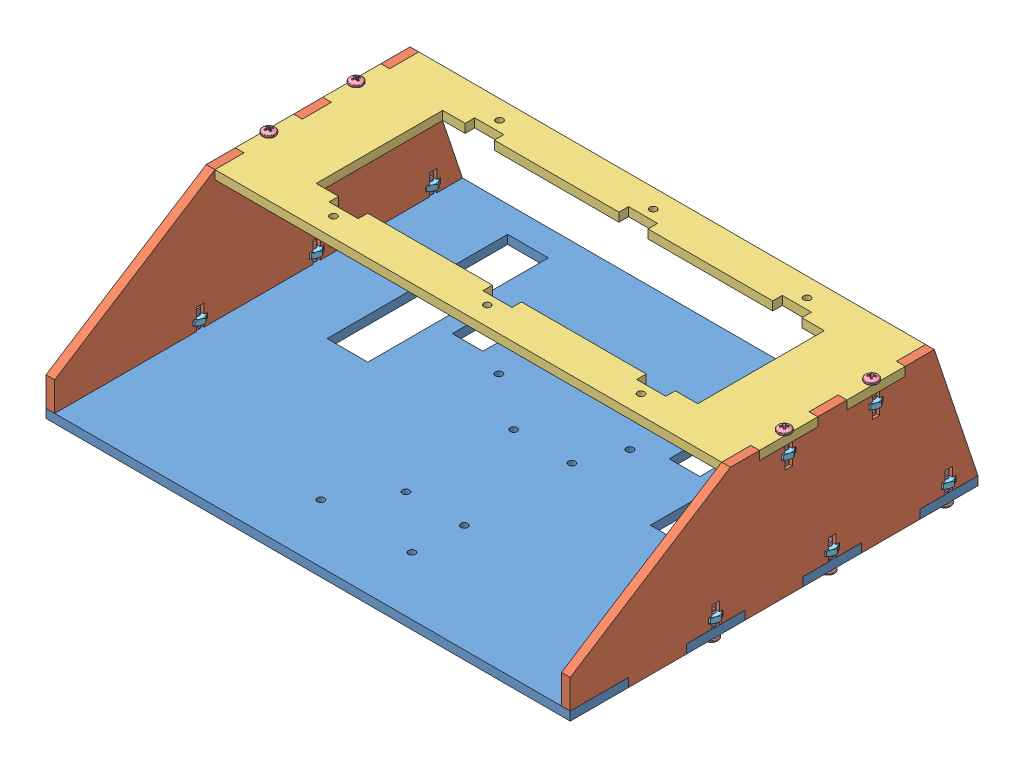
SolidWorks assembly Frame Assembly, configuration Default. Lengths in mm.
Overall size (233.62 64.89 177.8).
24 component instances, 5 part files, 52 mates.
Components (placement in the parent):
- Base Plate-1: Base Plate [Default] at (0 0 -88.9) x (-1 0 0) z (0 0 -1) size (228.6 3.81 177.8)
- Side Plate-1: Side Plate [Default] at (-114.3 0 -88.9) size (3.81 60.96 177.8)
- Side Plate-2: Side Plate [Default] at (110.49 0 -88.9) size (3.81 60.96 177.8)
- Top Plate-1: Top Plate [Default] at (0 57.15 -114.3) x (-1 0 0) z (0 0 -1) size (228.6 3.81 88.9)
- 91772A110_18-8 SS PAN HEAD PHILLIPS MACHINE SCREW-1: 91772A110_18-8 SS PAN HEAD PHILLIPS MACHINE SCREW [91772A110] at (112.395 12.7 -63.5) x (0.947469 0 0.319849) z (0 -1 0) size (5.56 5.56 14.77)
- 91772A110_18-8 SS PAN HEAD PHILLIPS MACHINE SCREW-2: 91772A110_18-8 SS PAN HEAD PHILLIPS MACHINE SCREW [91772A110] at (112.395 48.26 -133.35) x (-0.618252 0 -0.78598) z (0 1 0) size (5.56 5.56 14.77)
- 91772A110_18-8 SS PAN HEAD PHILLIPS MACHINE SCREW-3: 91772A110_18-8 SS PAN HEAD PHILLIPS MACHINE SCREW [91772A110] at (112.395 48.26 -95.25) x (-0.748146 0 -0.663534) z (0 1 0) size (5.56 5.56 14.77)
- 91772A110_18-8 SS PAN HEAD PHILLIPS MACHINE SCREW-4: 91772A110_18-8 SS PAN HEAD PHILLIPS MACHINE SCREW [91772A110] at (112.395 12.7 -114.3) x (0.947469 0 0.319849) z (0 -1 0) size (5.56 5.56 14.77)
- 91772A110_18-8 SS PAN HEAD PHILLIPS MACHINE SCREW-5: 91772A110_18-8 SS PAN HEAD PHILLIPS MACHINE SCREW [91772A110] at (112.395 12.7 -165.1) x (0.947469 0 0.319849) z (0 -1 0) size (5.56 5.56 14.77)
- 91772A110_18-8 SS PAN HEAD PHILLIPS MACHINE SCREW-11: 91772A110_18-8 SS PAN HEAD PHILLIPS MACHINE SCREW [91772A110] at (-112.395 12.7 -165.1) x (0.947469 0 0.319849) z (0 -1 0) size (5.56 5.56 14.77)
- 91772A110_18-8 SS PAN HEAD PHILLIPS MACHINE SCREW-12: 91772A110_18-8 SS PAN HEAD PHILLIPS MACHINE SCREW [91772A110] at (-112.395 48.26 -133.35) x (0.947469 0 0.319849) z (0 1 0) size (5.56 5.56 14.77)
- 91772A110_18-8 SS PAN HEAD PHILLIPS MACHINE SCREW-13: 91772A110_18-8 SS PAN HEAD PHILLIPS MACHINE SCREW [91772A110] at (-112.395 12.7 -63.5) x (0.947469 0 0.319849) z (0 -1 0) size (5.56 5.56 14.77)
- 91772A110_18-8 SS PAN HEAD PHILLIPS MACHINE SCREW-14: 91772A110_18-8 SS PAN HEAD PHILLIPS MACHINE SCREW [91772A110] at (-112.395 12.7 -114.3) x (0.947469 0 0.319849) z (0 -1 0) size (5.56 5.56 14.77)
- 91772A110_18-8 SS PAN HEAD PHILLIPS MACHINE SCREW-15: 91772A110_18-8 SS PAN HEAD PHILLIPS MACHINE SCREW [91772A110] at (-112.395 48.26 -95.25) x (0.947469 0 0.319849) z (0 1 0) size (5.56 5.56 14.77)
- 90480A005_LOW-STRENGTH STEEL HEX NUT-1: 90480A005_LOW-STRENGTH STEEL HEX NUT [90480A005] at (-112.395 7.5406 -165.1) x (-0.899638 0 -0.436636) z (0.436636 0 -0.899638) size (6.35 2.87 7.33)
- 90480A005_LOW-STRENGTH STEEL HEX NUT-2: 90480A005_LOW-STRENGTH STEEL HEX NUT [90480A005] at (-112.395 7.5406 -114.3) x (0.945332 0 0.326111) z (-0.326111 0 0.945332) size (6.35 2.87 7.33)
- 90480A005_LOW-STRENGTH STEEL HEX NUT-3: 90480A005_LOW-STRENGTH STEEL HEX NUT [90480A005] at (-112.395 53.4194 -95.25) x (0.945332 0 0.326111) z (-0.326111 0 0.945332) size (6.35 2.87 7.33)
- 90480A005_LOW-STRENGTH STEEL HEX NUT-4: 90480A005_LOW-STRENGTH STEEL HEX NUT [90480A005] at (112.395 7.5406 -114.3) x (0.917174 0 0.398486) z (-0.398486 0 0.917174) size (6.35 2.87 7.33)
- 90480A005_LOW-STRENGTH STEEL HEX NUT-5: 90480A005_LOW-STRENGTH STEEL HEX NUT [90480A005] at (112.395 7.5406 -63.5) x (0.945332 0 0.326111) z (-0.326111 0 0.945332) size (6.35 2.87 7.33)
- 90480A005_LOW-STRENGTH STEEL HEX NUT-6: 90480A005_LOW-STRENGTH STEEL HEX NUT [90480A005] at (-112.395 53.4194 -133.35) x (0.945332 0 0.326111) z (-0.326111 0 0.945332) size (6.35 2.87 7.33)
- 90480A005_LOW-STRENGTH STEEL HEX NUT-7: 90480A005_LOW-STRENGTH STEEL HEX NUT [90480A005] at (-112.395 7.5406 -63.5) x (0.945332 0 0.326111) z (-0.326111 0 0.945332) size (6.35 2.87 7.33)
- 90480A005_LOW-STRENGTH STEEL HEX NUT-8: 90480A005_LOW-STRENGTH STEEL HEX NUT [90480A005] at (112.395 7.5406 -165.1) x (0.945332 0 0.326111) z (-0.326111 0 0.945332) size (6.35 2.87 7.33)
- 90480A005_LOW-STRENGTH STEEL HEX NUT-9: 90480A005_LOW-STRENGTH STEEL HEX NUT [90480A005] at (112.395 53.4194 -95.25) x (0.945332 0 0.326111) z (-0.326111 0 0.945332) size (6.35 2.87 7.33)
- 90480A005_LOW-STRENGTH STEEL HEX NUT-10: 90480A005_LOW-STRENGTH STEEL HEX NUT [90480A005] at (112.395 53.4194 -133.35) x (0.945332 0 0.326111) z (-0.326111 0 0.945332) size (6.35 2.87 7.33)
Mates (geometry in assembly coordinates):
- Coincident7: coincident: plane of Base Plate-1 through (-110.49 3.81 -25.4) normal (-1 0 0); plane of Side Plate-1 through (-110.49 0 -88.9) normal (1 0 0)
- Coincident8: coincident: plane of Base Plate-1 through (-110.49 3.81 -50.8) normal (0 0 1); plane of Side Plate-1 through (-110.49 0 -50.8) normal (0 0 -1)
- Coincident9: coincident: plane of Base Plate-1 through (0 0 -88.9) normal (0 -1 0); plane of Side Plate-1 through (-110.49 0 -25.4) normal (0 -1 0)
- Coincident13: coincident: plane of Base Plate-1 through (110.49 3.81 -25.4) normal (1 0 0); plane of Side Plate-2 through (110.49 0 -88.9) normal (-1 0 0)
- Coincident14: coincident: plane of Base Plate-1 through (0 0 -88.9) normal (0 -1 0); plane of Side Plate-2 through (114.3 0 -25.4) normal (0 -1 0)
- Coincident15: coincident: plane of Base Plate-1 through (110.49 3.81 -50.8) normal (0 0 1); plane of Side Plate-2 through (114.3 0 -50.8) normal (0 0 -1)
- Coincident19: coincident: plane of Side Plate-2 through (114.3 57.15 -96.8375) normal (0 1 0); plane of Top Plate-1 through (0 57.15 -114.3) normal (0 -1 0)
- Coincident20: coincident: plane of Side Plate-2 through (114.3 57.15 -107.95) normal (0 0 1); plane of Top Plate-1 through (110.49 60.96 -107.95) normal (0 0 -1)
- Coincident21: coincident: plane of Side Plate-2 through (114.3 0 -88.9) normal (1 0 0); plane of Top Plate-1 through (114.3 60.96 -107.95) normal (1 0 0)
- Coincident22: coincident: plane of Base Plate-1 through (0 0 -88.9) normal (0 -1 0); plane of 91772A110_18-8 SS PAN HEAD PHILLIPS MACHINE SCREW-1 through (112.395 0 -63.5) normal (0 1 0)
- Coincident23: coincident: plane of Base Plate-1 through (0 0 -88.9) normal (0 -1 0); plane of 91772A110_18-8 SS PAN HEAD PHILLIPS MACHINE SCREW-4 through (112.395 0 -114.3) normal (0 1 0)
- Coincident24: coincident: plane of Base Plate-1 through (0 0 -88.9) normal (0 -1 0); plane of 91772A110_18-8 SS PAN HEAD PHILLIPS MACHINE SCREW-5 through (112.395 0 -165.1) normal (0 1 0)
- Concentric12: concentric: circle of Top Plate-1; circle of 91772A110_18-8 SS PAN HEAD PHILLIPS MACHINE SCREW-2
- Coincident25: coincident: plane of Top Plate-1 through (0 60.96 -114.3) normal (0 1 0); plane of 91772A110_18-8 SS PAN HEAD PHILLIPS MACHINE SCREW-2 through (112.395 60.96 -133.35) normal (0 -1 0)
- Concentric13: concentric: circle of Top Plate-1; circle of 91772A110_18-8 SS PAN HEAD PHILLIPS MACHINE SCREW-3
- Coincident26: coincident: plane of Top Plate-1 through (0 60.96 -114.3) normal (0 1 0); plane of 91772A110_18-8 SS PAN HEAD PHILLIPS MACHINE SCREW-3 through (112.395 60.96 -95.25) normal (0 -1 0)
- Concentric14: concentric: cylinder of Base Plate-1 through (112.395 3.81 -63.5) axis (0 -1 0) radius 1.524; cylinder of 91772A110_18-8 SS PAN HEAD PHILLIPS MACHINE SCREW-1 through (112.395 12.7 -63.5) axis (0 1 0) radius 2.7813
- Concentric15: concentric: circle of Base Plate-1; circle of 91772A110_18-8 SS PAN HEAD PHILLIPS MACHINE SCREW-4
- Concentric16: concentric: circle of Base Plate-1; circle of 91772A110_18-8 SS PAN HEAD PHILLIPS MACHINE SCREW-5
- Coincident27: coincident: plane of Base Plate-1 through (0 0 -88.9) normal (0 -1 0); plane of 91772A110_18-8 SS PAN HEAD PHILLIPS MACHINE SCREW-11 through (-112.395 0 -165.1) normal (0 1 0)
- Concentric17: concentric: circle of Base Plate-1; circle of 91772A110_18-8 SS PAN HEAD PHILLIPS MACHINE SCREW-11
- Coincident28: coincident: plane of Base Plate-1 through (0 0 -88.9) normal (0 -1 0); plane of 91772A110_18-8 SS PAN HEAD PHILLIPS MACHINE SCREW-14 through (-112.395 0 -114.3) normal (0 1 0)
- Concentric18: concentric: cylinder of Base Plate-1 through (-112.395 3.81 -114.3) axis (0 -1 0) radius 1.524; circle of 91772A110_18-8 SS PAN HEAD PHILLIPS MACHINE SCREW-14
- Coincident29: coincident: plane of Base Plate-1 through (0 0 -88.9) normal (0 -1 0); plane of 91772A110_18-8 SS PAN HEAD PHILLIPS MACHINE SCREW-13 through (-112.395 0 -63.5) normal (0 1 0)
- Concentric19: concentric: circle of Base Plate-1; circle of 91772A110_18-8 SS PAN HEAD PHILLIPS MACHINE SCREW-13
- Coincident30: coincident: plane of Top Plate-1 through (0 60.96 -114.3) normal (0 1 0); plane of 91772A110_18-8 SS PAN HEAD PHILLIPS MACHINE SCREW-12 through (-112.395 60.96 -133.35) normal (0 -1 0)
- Concentric20: concentric: circle of Top Plate-1; circle of 91772A110_18-8 SS PAN HEAD PHILLIPS MACHINE SCREW-12
- Coincident31: coincident: plane of Top Plate-1 through (0 60.96 -114.3) normal (0 1 0); plane of 91772A110_18-8 SS PAN HEAD PHILLIPS MACHINE SCREW-15 through (-112.395 60.96 -95.25) normal (0 -1 0)
- Concentric21: concentric: circle of Top Plate-1; circle of 91772A110_18-8 SS PAN HEAD PHILLIPS MACHINE SCREW-15
- Concentric22: concentric: circle of 91772A110_18-8 SS PAN HEAD PHILLIPS MACHINE SCREW-11; circle of 90480A005_LOW-STRENGTH STEEL HEX NUT-1
- Coincident32: coincident: plane of Side Plate-1 through (-110.49 6.35 -168.2242) normal (0 1 0); plane of 90480A005_LOW-STRENGTH STEEL HEX NUT-1 through (-110.339 6.35 -162.0646) normal (0 -1 0)
- Concentric23: concentric: circle of 91772A110_18-8 SS PAN HEAD PHILLIPS MACHINE SCREW-14; circle of 90480A005_LOW-STRENGTH STEEL HEX NUT-2
- Coincident35: coincident: plane of Side Plate-1 through (-110.49 6.35 -112.7125) normal (0 1 0); plane of 90480A005_LOW-STRENGTH STEEL HEX NUT-2 through (-114.7986 6.35 -117.0683) normal (0 -1 0)
- Concentric24: concentric: circle of 91772A110_18-8 SS PAN HEAD PHILLIPS MACHINE SCREW-13; circle of 90480A005_LOW-STRENGTH STEEL HEX NUT-7
- Coincident36: coincident: plane of Side Plate-1 through (-110.49 6.35 -61.9125) normal (0 1 0); plane of 90480A005_LOW-STRENGTH STEEL HEX NUT-7 through (-114.7986 6.35 -66.2683) normal (0 -1 0)
- Concentric25: concentric: circle of 91772A110_18-8 SS PAN HEAD PHILLIPS MACHINE SCREW-12; circle of 90480A005_LOW-STRENGTH STEEL HEX NUT-6
- Coincident37: coincident: plane of Side Plate-1 through (-110.49 54.61 -131.7625) normal (0 -1 0); plane of 90480A005_LOW-STRENGTH STEEL HEX NUT-6 through (-114.7986 54.61 -136.1183) normal (0 1 0)
- Concentric26: concentric: circle of 91772A110_18-8 SS PAN HEAD PHILLIPS MACHINE SCREW-15; circle of 90480A005_LOW-STRENGTH STEEL HEX NUT-3
- Coincident38: coincident: plane of Side Plate-1 through (-110.49 54.61 -93.6625) normal (0 -1 0); plane of 90480A005_LOW-STRENGTH STEEL HEX NUT-3 through (-114.7986 54.61 -98.0183) normal (0 1 0)
- Concentric27: concentric: circle of 91772A110_18-8 SS PAN HEAD PHILLIPS MACHINE SCREW-1; circle of 90480A005_LOW-STRENGTH STEEL HEX NUT-5
- Coincident40: coincident: plane of Side Plate-2 through (114.3 6.35 -61.9125) normal (0 1 0); plane of 90480A005_LOW-STRENGTH STEEL HEX NUT-5 through (109.9914 6.35 -66.2683) normal (0 -1 0)
- Concentric28: concentric: circle of 91772A110_18-8 SS PAN HEAD PHILLIPS MACHINE SCREW-4; circle of 90480A005_LOW-STRENGTH STEEL HEX NUT-4
- Coincident41: coincident: plane of Side Plate-2 through (114.3 6.35 -112.7125) normal (0 1 0); plane of 90480A005_LOW-STRENGTH STEEL HEX NUT-4 through (110.2134 6.35 -117.2465) normal (0 -1 0)
- Concentric29: concentric: circle of 91772A110_18-8 SS PAN HEAD PHILLIPS MACHINE SCREW-5; circle of 90480A005_LOW-STRENGTH STEEL HEX NUT-8
- Coincident42: coincident: plane of Side Plate-2 through (114.3 6.35 -163.5125) normal (0 1 0); plane of 90480A005_LOW-STRENGTH STEEL HEX NUT-8 through (109.9914 6.35 -167.8683) normal (0 -1 0)
- Concentric30: concentric: circle of 91772A110_18-8 SS PAN HEAD PHILLIPS MACHINE SCREW-3; circle of 90480A005_LOW-STRENGTH STEEL HEX NUT-9
- Coincident43: coincident: plane of Side Plate-2 through (114.3 54.61 -98.3742) normal (0 -1 0); plane of 90480A005_LOW-STRENGTH STEEL HEX NUT-9 through (109.9914 54.61 -98.0183) normal (0 1 0)
- Concentric31: concentric: circle of 91772A110_18-8 SS PAN HEAD PHILLIPS MACHINE SCREW-2; circle of 90480A005_LOW-STRENGTH STEEL HEX NUT-10
- Coincident44: coincident: plane of Side Plate-2 through (114.3 54.61 -136.4742) normal (0 -1 0); plane of 90480A005_LOW-STRENGTH STEEL HEX NUT-10 through (109.9914 54.61 -136.1183) normal (0 1 0)
- Coincident45: coincident: plane of Base Plate-1 through (0 0 -88.9) normal (-1 0 0); plane of assembly through (0 0 0) normal (1 0 0)
- Coincident47: coincident: plane of Base Plate-1 through (114.3 3.81 0) normal (0 0 1); plane of assembly through (0 0 0) normal (0 0 1)
- Coincident50: coincident: plane of Base Plate-1 through (0 0 -88.9) normal (0 -1 0); plane of assembly through (0 0 0) normal (0 1 0)
